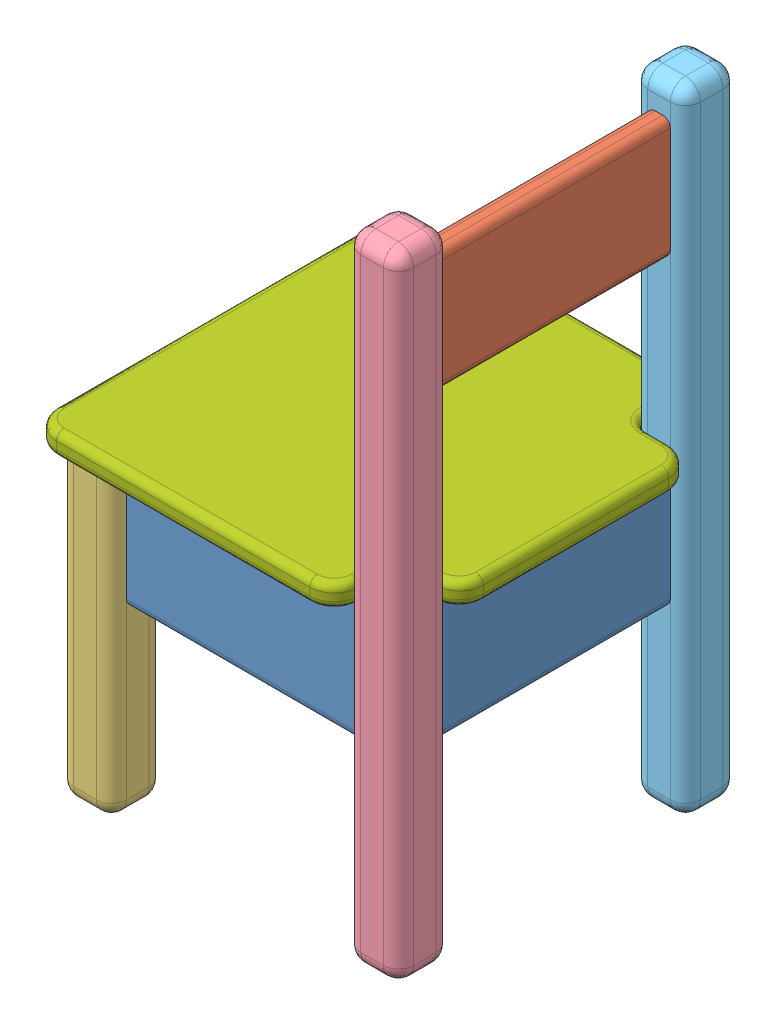
SolidWorks assembly chair assembly, configuration Default. Lengths in mm.
Overall size (304.8 533.4 304.8).
30 component instances, 7 part files, 69 mates.
Components (placement in the parent):
- bottom 775-1: bottom 775 [Default] at (75.3393 203.2 -142.875) x (0 1 0) z (0 0 1) size (101.6 19.05 196.85)
- bottom 775-2: bottom 775 [Default] at (-45.3107 203.2 -263.525) x (0 1 0) z (1 0 0) size (101.6 19.05 196.85)
- bottom 775-3: bottom 775 [Default] at (-165.9607 203.2 -142.875) x (0 1 0) z (0 0 -1) size (101.6 19.05 196.85)
- bottom 775-4: bottom 775 [Default] at (-45.3107 203.2 -22.225) x (0 1 0) z (-1 0 0) size (101.6 19.05 196.85)
- top 775-1: top 775 [Default] at (75.3393 457.2 -142.875) x (0 -1 0) z (0 0 -1) size (101.6 19.05 196.85)
- 10 in leg-1: 10 in leg [Default] at (-165.9607 0 -263.525) x (0 0 1) z (0 1 0) size (44.45 44.45 254)
- 10 in leg-2: 10 in leg [Default] at (-165.9607 0 -22.225) x (1 0 0) z (0 1 0) size (44.45 44.45 254)
- L21 in leg-1: L21 in leg [Default] at (75.3393 0 -22.225) x (0 0 -1) z (0 1 0) size (44.45 44.45 533.4)
- R21 in leg-1: R21 in leg [Default] at (75.3393 0 -263.525) x (-1 0 0) z (0 1 0) size (44.45 44.45 533.4)
- dowel-1: dowel [Default] at (-156.4357 228.6 -263.525) x (0 0.012192 0.999926) z (0 0.999926 -0.012192) size (6.35 25.4 6.35)
- dowel-2: dowel [Default] at (-156.4357 177.8 -263.525) x (0 0.012192 0.999926) z (0 0.999926 -0.012192) size (6.35 25.4 6.35)
- dowel-3: dowel [Default] at (-165.9607 228.6 -254) x (0.812589 -0.582837 0) z (-0.582837 -0.812589 0) size (6.35 25.4 6.35)
- dowel-4: dowel [Default] at (-165.9607 177.8 -254) x (0.812589 -0.582837 0) z (-0.582837 -0.812589 0) size (6.35 25.4 6.35)
- dowel-5: dowel [Default] at (-165.9607 177.8 -31.75) x (0.228386 0.973571 0) z (-0.973571 0.228386 0) size (6.35 25.4 6.35)
- dowel-6: dowel [Default] at (-165.9607 228.6 -31.75) x (0.228386 0.973571 0) z (-0.973571 0.228386 0) size (6.35 25.4 6.35)
- dowel-7: dowel [Default] at (-156.4357 228.6 -22.225) x (0 0.54577 -0.837935) z (0 -0.837935 -0.54577) size (6.35 25.4 6.35)
- dowel-8: dowel [Default] at (-156.4357 177.8 -22.225) x (0 0.54577 -0.837935) z (0 -0.837935 -0.54577) size (6.35 25.4 6.35)
- dowel-9: dowel [Default] at (75.3393 177.8 -254) x (-0.899097 0.43775 0) z (0.43775 0.899097 0) size (6.35 25.4 6.35)
- dowel-10: dowel [Default] at (75.3393 228.6 -254) x (-0.899097 0.43775 0) z (0.43775 0.899097 0) size (6.35 25.4 6.35)
- dowel-11: dowel [Default] at (65.8143 177.8 -263.525) x (0 -0.868019 -0.49653) z (0 0.49653 -0.868019) size (6.35 25.4 6.35)
- dowel-12: dowel [Default] at (65.8143 228.6 -263.525) x (0 -0.868019 -0.49653) z (0 0.49653 -0.868019) size (6.35 25.4 6.35)
- dowel-13: dowel [Default] at (65.8143 177.8 -22.225) x (0 -0.228213 0.973611) z (0 -0.973611 -0.228213) size (6.35 25.4 6.35)
- dowel-14: dowel [Default] at (65.8143 228.6 -22.225) x (0 -0.228213 0.973611) z (0 -0.973611 -0.228213) size (6.35 25.4 6.35)
- dowel-15: dowel [Default] at (75.3393 177.8 -31.75) x (0.899097 -0.43775 0) z (0.43775 0.899097 0) size (6.35 25.4 6.35)
- dowel-16: dowel [Default] at (75.3393 228.6 -31.75) x (0.899097 -0.43775 0) z (0.43775 0.899097 0) size (6.35 25.4 6.35)
- dowel-17: dowel [Default] at (75.3393 431.8 -254) x (-0.899097 0.43775 0) z (0.43775 0.899097 0) size (6.35 25.4 6.35)
- dowel-18: dowel [Default] at (75.3393 482.6 -254) x (-0.899097 0.43775 0) z (0.43775 0.899097 0) size (6.35 25.4 6.35)
- dowel-19: dowel [Default] at (75.3393 431.8 -31.75) x (0.899097 -0.43775 0) z (0.43775 0.899097 0) size (6.35 25.4 6.35)
- dowel-20: dowel [Default] at (75.3393 482.6 -31.75) x (0.899097 -0.43775 0) z (0.43775 0.899097 0) size (6.35 25.4 6.35)
- seat-1: seat [Default] at (-48.4857 254 -142.875) x (0 0 -1) z (0 1 0) size (304.8 304.8 19.05)
Mates (geometry in assembly coordinates):
- Concentric1: concentric: cylinder of ? through (-108.6471 177.8 -113.1573) axis (0.636906 0 0.770941) radius 3.175; cylinder of ? through (-92.4697 177.8 -93.5754) axis (-0.636906 0 -0.770941) radius 3.175
- Concentric2: concentric: cylinder of ? through (-108.6471 228.6 -113.1573) axis (0.636906 0 0.770941) radius 3.175; cylinder of ? through (-92.4697 228.6 -93.5754) axis (-0.636906 0 -0.770941) radius 3.175
- Concentric3: concentric: circle of ?; cylinder of ? through (-141.6388 177.8 -98.2566) axis (0.770941 0 -0.636906) radius 3.175
- Concentric4: concentric: cylinder of ? through (-122.0569 228.6 -114.434) axis (-0.770941 0 0.636906) radius 3.175; cylinder of ? through (-141.6388 228.6 -98.2566) axis (0.770941 0 -0.636906) radius 3.175
- Concentric5: concentric: circle of ?; cylinder of ? through (-273.8167 228.6 10.941) axis (-0.770941 0 0.636906) radius 3.175
- Concentric6: concentric: cylinder of ? through (-293.3986 177.8 27.1184) axis (0.770941 0 -0.636906) radius 3.175; cylinder of ? through (-273.8167 177.8 10.941) axis (-0.770941 0 0.636906) radius 3.175
- Concentric7: concentric: cylinder of ? through (-294.6753 177.8 40.5281) axis (0.636906 0 0.770941) radius 3.175; cylinder of ? through (-278.4979 177.8 60.1101) axis (-0.636906 0 -0.770941) radius 3.175
- Concentric8: concentric: cylinder of ? through (-294.6753 228.6 40.5281) axis (0.636906 0 0.770941) radius 3.175; cylinder of ? through (-278.4979 228.6 60.1101) axis (-0.636906 0 -0.770941) radius 3.175
- Distance1: distance = 12.7 mm: plane of assembly; plane of assembly; plane of dowel-2 through (-131.0357 177.8 -263.525) normal (1 0 0); plane of 10 in leg-1 through (-143.7357 254 -273.05) normal (1 0 0)
- Distance2: distance = 12.7 mm: plane of assembly; plane of assembly; plane of dowel-1 through (-131.0357 228.6 -263.525) normal (1 0 0); plane of 10 in leg-1 through (-143.7357 254 -273.05) normal (1 0 0)
- Distance3: distance = 12.7 mm: plane of assembly; plane of assembly; plane of dowel-6 through (-165.9607 228.6 -57.15) normal (0 0 -1); plane of 10 in leg-2 through (-175.4857 254 -44.45) normal (0 0 -1)
- Coincident1: coincident: unknown of ?; circle of ?
- Coincident2: coincident: line of ? through (-141.6388 228.6 -98.2566) axis (-0.770941 0 0.636906); line of ? through (-141.6388 177.8 -98.2566) axis (-0.770941 0 0.636906)
- Distance4: distance = 12.7 mm: plane of assembly; plane of assembly; plane of dowel-3 through (-165.9607 228.6 -228.6) normal (0 0 1); plane of 10 in leg-1 through (-175.4857 254 -241.3) normal (0 0 1)
- Distance5: distance = 12.7 mm: plane of assembly; plane of assembly; plane of dowel-7 through (-131.0357 228.6 -22.225) normal (1 0 0); plane of 10 in leg-2 through (-143.7357 254 -12.7) normal (1 0 0)
- Coincident3: coincident: unknown of ?; unknown of ?
- Concentric9: concentric: cylinder of ? through (-278.4979 177.8 60.1101) axis (-0.636906 0 -0.770941) radius 3.175; cylinder of ? through (-278.4979 177.8 60.1101) axis (-0.636906 0 -0.770941) radius 3.175
- Concentric10: concentric: cylinder of ? through (-278.4979 228.6 60.1101) axis (-0.636906 0 -0.770941) radius 3.175; cylinder of ? through (-278.4979 228.6 60.1101) axis (-0.636906 0 -0.770941) radius 3.175
- Coincident4: coincident: unknown of ?; unknown of ?
- Concentric11: concentric: cylinder of ? through (-273.8167 177.8 10.941) axis (-0.770941 0 0.636906) radius 3.175; cylinder of ? through (-273.8167 177.8 10.941) axis (-0.770941 0 0.636906) radius 3.175
- Concentric12: concentric: cylinder of ? through (-273.8167 228.6 10.941) axis (-0.770941 0 0.636906) radius 3.175; cylinder of ? through (-273.8167 228.6 10.941) axis (-0.770941 0 0.636906) radius 3.175
- Coincident5: coincident: line of ? through (-285.6298 158.75 16.582) axis (-0.770941 0 0.636906); unknown of ?
- Concentric13: concentric: cylinder of ? through (-141.6388 228.6 -98.2566) axis (0.770941 0 -0.636906) radius 3.175; cylinder of ? through (-141.6388 228.6 -98.2566) axis (0.770941 0 -0.636906) radius 3.175
- Concentric14: concentric: cylinder of ? through (-141.6388 177.8 -98.2566) axis (0.770941 0 -0.636906) radius 3.175; cylinder of ? through (-141.6388 177.8 -98.2566) axis (0.770941 0 -0.636906) radius 3.175
- Coincident6: coincident: unknown of ?; line of ? through (-137.9144 254 -113.6885) axis (-0.770941 0 0.636906)
- Concentric15: concentric: cylinder of ? through (-92.4697 228.6 -93.5754) axis (-0.636906 0 -0.770941) radius 3.175; cylinder of ? through (-92.4697 228.6 -93.5754) axis (-0.636906 0 -0.770941) radius 3.175
- Concentric16: concentric: cylinder of ? through (-92.4697 177.8 -93.5754) axis (-0.636906 0 -0.770941) radius 3.175; cylinder of ? through (-92.4697 177.8 -93.5754) axis (-0.636906 0 -0.770941) radius 3.175
- Coincident7: coincident: unknown of ?; unknown of ?
- Concentric17: concentric: circle of ?; cylinder of ? through (12.0467 482.6 87.7716) axis (0.770941 0 -0.636906) radius 3.175
- Concentric18: concentric: circle of ?; cylinder of ? through (12.0467 431.8 87.7716) axis (0.770941 0 -0.636906) radius 3.175
- Concentric19: concentric: circle of ?; cylinder of ? through (12.0467 228.6 87.7716) axis (0.770941 0 -0.636906) radius 3.175
- Concentric20: concentric: circle of ?; cylinder of ? through (12.0467 177.8 87.7716) axis (0.770941 0 -0.636906) radius 3.175
- Coincident8: coincident: line of ? through (12.0467 431.8 87.7716) axis (-0.770941 0 0.636906); line of ? through (12.0467 482.6 87.7716) axis (-0.770941 0 0.636906)
- Coincident9: coincident: line of ? through (12.0467 228.6 87.7716) axis (-0.770941 0 0.636906); line of ? through (12.0467 431.8 87.7716) axis (-0.770941 0 0.636906)
- Coincident10: coincident: line of ? through (12.0467 177.8 87.7716) axis (-0.770941 0 0.636906); line of ? through (12.0467 228.6 87.7716) axis (-0.770941 0 0.636906)
- Distance6: distance = 12.7 mm: plane of assembly; plane of assembly; plane of dowel-17 through (75.3393 431.8 -228.6) normal (0 0 1); plane of R21 in leg-1 through (84.8643 254 -241.3) normal (0 0 1)
- Concentric21: concentric: cylinder of ? through (32.9053 228.6 58.1844) axis (-0.636906 0 -0.770941) radius 3.175; cylinder of ? through (16.7278 228.6 38.6025) axis (0.636906 0 0.770941) radius 3.175
- Concentric22: concentric: cylinder of ? through (32.9053 177.8 58.1844) axis (-0.636906 0 -0.770941) radius 3.175; cylinder of ? through (16.7278 177.8 38.6025) axis (0.636906 0 0.770941) radius 3.175
- Coincident11: coincident: unknown of ?; unknown of ?
- Distance7: distance = 12.7 mm: plane of assembly; plane of assembly; plane of dowel-12 through (40.4143 228.6 -263.525) normal (-1 0 0); plane of R21 in leg-1 through (53.1143 254 -273.05) normal (-1 0 0)
- Concentric23: concentric: cylinder of ? through (-139.7131 228.6 213.1465) axis (0.770941 0 -0.636906) radius 3.175; cylinder of ? through (-120.1312 228.6 196.9691) axis (-0.770941 0 0.636906) radius 3.175
- Concentric24: concentric: cylinder of ? through (-139.7131 177.8 213.1465) axis (0.770941 0 -0.636906) radius 3.175; cylinder of ? through (-120.1312 177.8 196.9691) axis (-0.770941 0 0.636906) radius 3.175
- Concentric25: concentric: circle of ?; cylinder of ? through (-169.3003 177.8 192.288) axis (0.636906 0 0.770941) radius 3.175
- Concentric26: concentric: cylinder of ? through (-153.1229 228.6 211.8699) axis (-0.636906 0 -0.770941) radius 3.175; cylinder of ? through (-169.3003 228.6 192.288) axis (0.636906 0 0.770941) radius 3.175
- Concentric27: concentric: cylinder of ? through (-139.7131 431.8 213.1465) axis (0.770941 0 -0.636906) radius 3.175; cylinder of ? through (-120.1312 431.8 196.9691) axis (-0.770941 0 0.636906) radius 3.175
- Concentric28: concentric: cylinder of ? through (-139.7131 482.6 213.1465) axis (0.770941 0 -0.636906) radius 3.175; cylinder of ? through (-120.1312 482.6 196.9691) axis (-0.770941 0 0.636906) radius 3.175
- Coincident12: coincident: unknown of ?; unknown of ?
- Coincident13: coincident: unknown of ?; unknown of ?
- Coincident14: coincident: unknown of ?; unknown of ?
- Distance9: distance = 12.7 mm: plane of assembly; plane of assembly; plane of dowel-19 through (75.3393 431.8 -57.15) normal (0 0 -1); plane of L21 in leg-1 through (84.8643 254 -44.45) normal (0 0 -1)
- Coincident15: coincident: unknown of ?; unknown of ?
- Distance10: distance = 12.7 mm: plane of assembly; plane of assembly; plane of dowel-14 through (40.4143 228.6 -22.225) normal (-1 0 0); plane of L21 in leg-1 through (53.1143 254 -12.7) normal (-1 0 0)
- Concentric29: concentric: cylinder of ? through (12.0467 482.6 87.7716) axis (0.770941 0 -0.636906) radius 3.175; cylinder of ? through (-120.1312 482.6 196.9691) axis (-0.770941 0 0.636906) radius 3.175
- Concentric30: concentric: cylinder of ? through (12.0467 431.8 87.7716) axis (0.770941 0 -0.636906) radius 3.175; cylinder of ? through (-120.1312 431.8 196.9691) axis (-0.770941 0 0.636906) radius 3.175
- Concentric31: concentric: circle of ?; cylinder of ? through (-120.1312 482.6 196.9691) axis (-0.770941 0 0.636906) radius 3.175
- Concentric32: concentric: circle of ?; cylinder of ? through (12.0467 431.8 87.7716) axis (0.770941 0 -0.636906) radius 3.175
- Coincident16: coincident: unknown of ?; line of ? through (27.9042 254 87.0261) axis (-0.770941 0 0.636906)
- Concentric33: concentric: cylinder of ? through (-120.1312 228.6 196.9691) axis (-0.770941 0 0.636906) radius 3.175; cylinder of ? through (-120.1312 228.6 196.9691) axis (-0.770941 0 0.636906) radius 3.175
- Concentric34: concentric: circle of ?; cylinder of ? through (12.0467 177.8 87.7716) axis (0.770941 0 -0.636906) radius 3.175
- Coincident17: coincident: unknown of ?; line of ? through (27.9042 254 87.0261) axis (-0.770941 0 0.636906)
- Coincident18: coincident: line of ? through (-127.9 158.75 207.5056) axis (-0.770941 0 0.636906); unknown of ?
- Coincident19: coincident: plane of ? through (-127.9 254 207.5056) normal (0 1 0); plane of ? through (27.2643 254 46.3713) normal (0 1 0)
- Coincident20: coincident: unknown of ?; unknown of ?
- Concentric36: concentric: circle of ?; cylinder of ? through (16.7278 228.6 38.6025) axis (0.636906 0 0.770941) radius 3.175
- Coincident21: coincident: plane of ? through (-289.0343 254 52.3413) normal (0 1 0); plane of ? through (25.562 254 64.2509) normal (0 -1 0)
- Coincident22: coincident: line of ? through (27.9042 254 87.0261) axis (-0.770941 0 0.636906); unknown of ?
- Coincident23: coincident: unknown of ?; unknown of ?
- Coincident24: coincident: plane of ? through (-113.437 0 -133.9103) normal (0 -1 0)
- Coincident25: coincident: plane of assembly; plane of L21 in leg-1 through (84.8643 254 0) normal (0 0 1); plane of assembly
